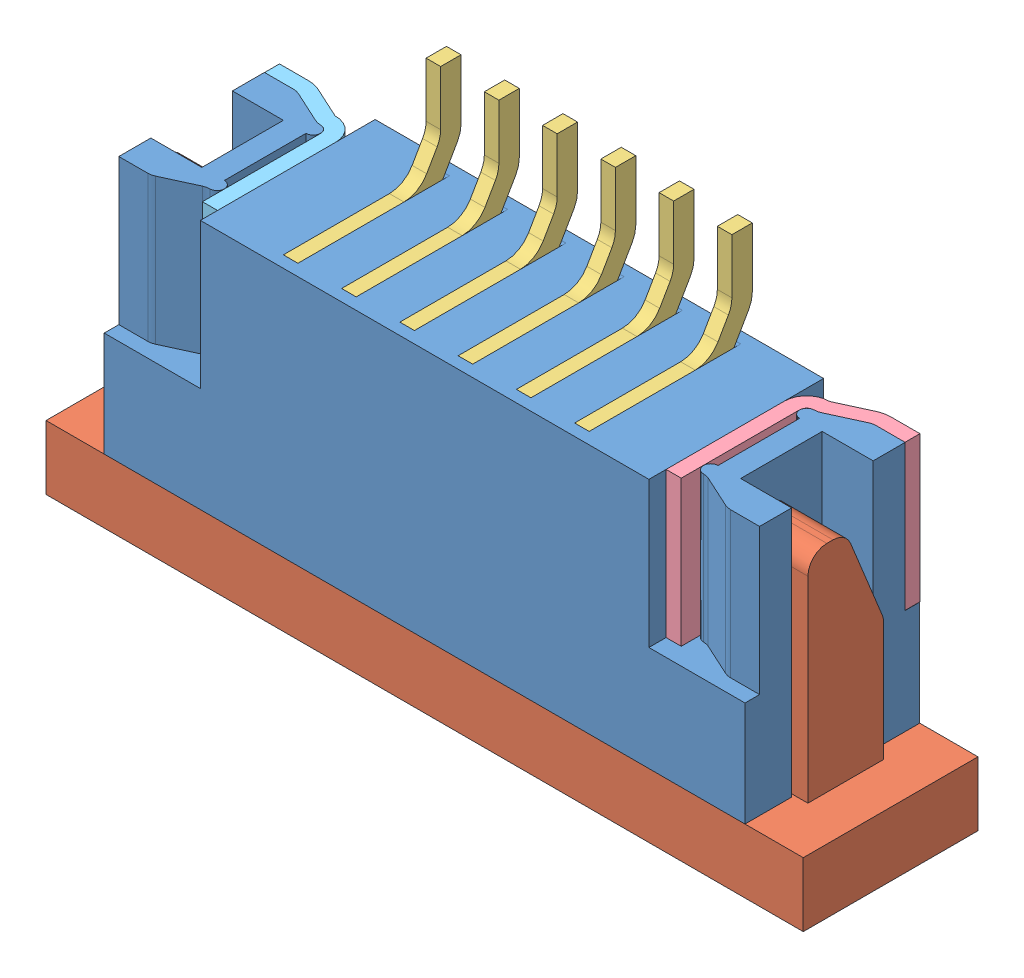
SolidWorks assembly 68610614422 (rev1), configuration Défaut. Lengths in mm.
Overall size (13 7.1 3.01).
10 component instances, 5 part files, 0 mates.
Components (placement in the parent):
- Gehõuse_3-1: Gehõuse_3 [Défaut] at origin size (11 5.4 3)
- Verschluss_3-1: Verschluss_3 [Défaut] at (0 -3.25 0) x (1 0 0) z (0 1 0) size (13 3 4.8)
- Pin1_3-1: Pin1_3 [Défaut] at (-1.5 0 0) x (-1 0 0) z (0 0 1) size (0.25 6 2.8)
- Pin1_3-2: Pin1_3 [Défaut] at (-2.5 0 0) x (-1 0 0) z (0 0 1) size (0.25 6 2.8)
- Pin1_3-3: Pin1_3 [Défaut] at (-0.5 0 0) x (-1 0 0) z (0 0 1) size (0.25 6 2.8)
- Pin1_3-4: Pin1_3 [Défaut] at (1.5 0 0) x (-1 0 0) z (0 0 1) size (0.25 6 2.8)
- Pin1_3-5: Pin1_3 [Défaut] at (2.5 0 0) x (-1 0 0) z (0 0 1) size (0.25 6 2.8)
- Pin1_3-6: Pin1_3 [Défaut] at (0.5 0 0) x (-1 0 0) z (0 0 1) size (0.25 6 2.8)
- Pin_rechts_3-1: Pin_rechts_3 [Défaut] at (3.98 0.9 0) x (-1 0 0) z (0 1 0) size (1.65 2.71 2.5)
- Pin_rechts_mir_3-1: Pin_rechts_mir_3 [Défaut] at (-3.98 0.9 0) x (1 0 0) z (0 1 0) size (1.65 2.71 2.5)
